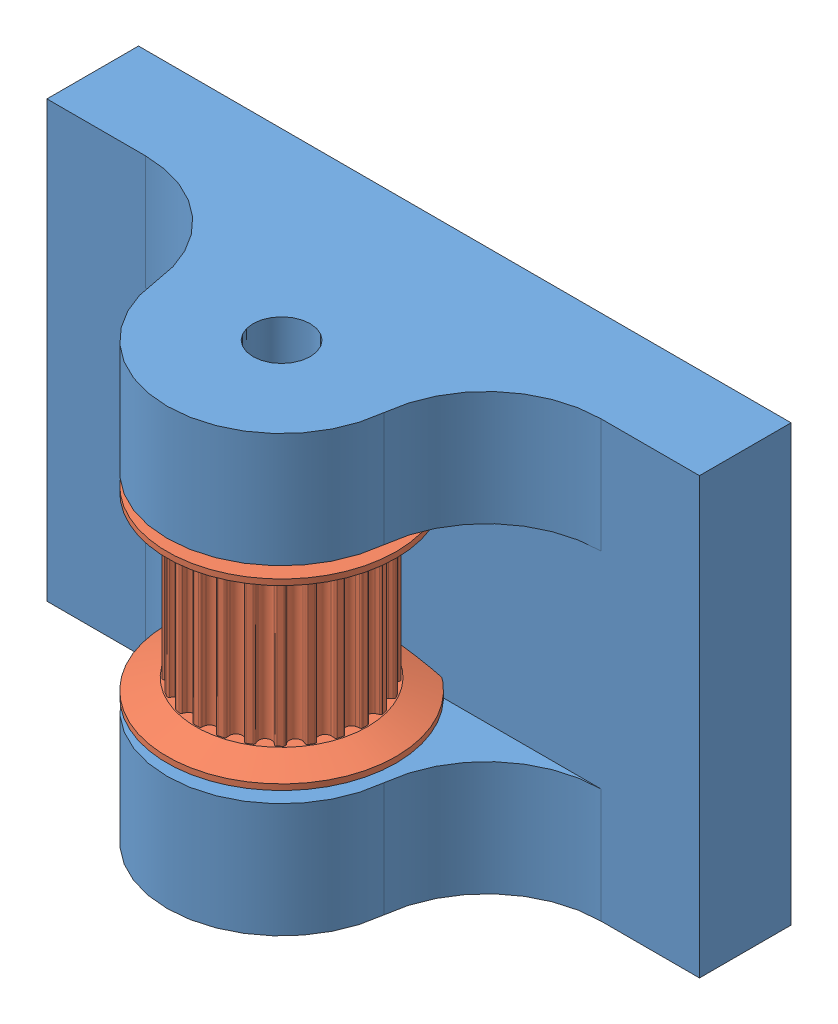
SolidWorks assembly Idler Assembly, configuration Right. Lengths in mm.
Overall size (57 38 29.01).
2 component instances, 2 part files, 2 mates.
Components (placement in the parent):
- Idler Bracket^Idler Assembly-1: Idler Bracket^Idler Assembly [Right] at origin size (57 38 26) (virtual)
- GT2 IdlerT24 W12 Ø10_Printable-1: GT2 IdlerT24 W12 Ø10_Printable [W12 Ø5] at (0 8 16) x (0.927724 0 -0.373267) z (0 -1 0) size (20 20 16)
Mates (geometry in assembly coordinates):
- Concentric1: concentric anti-aligned: cylinder of Idler Bracket^Idler Assembly_XYRail Assembly_XGantry-1 through (0 8 16) axis (0 1 0) radius 2.5; cylinder of GT2 IdlerT24 W12 Ø10_Printable-1 through (0 8 16) axis (0 -1 0) radius 2.5
- Coincident2: coincident anti-aligned: plane of Idler Bracket^Idler Assembly_XYRail Assembly_XGantry-1 through (0 8 16) normal (0 -1 0); plane of GT2 IdlerT24 W12 Ø10_Printable-1 through (0 8 16) normal (0 1 0)
